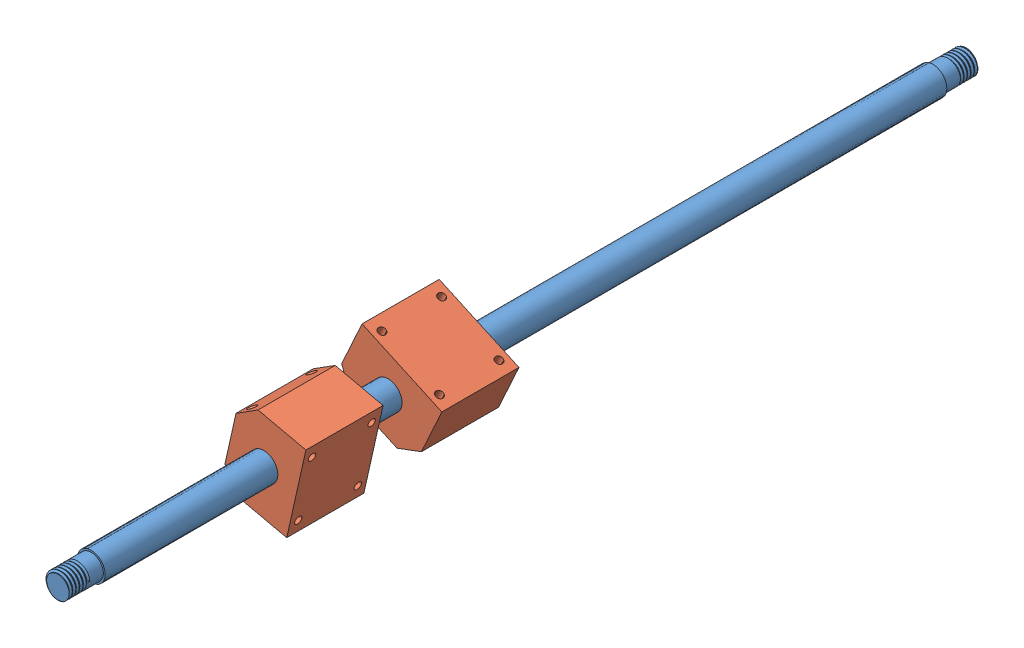
SolidWorks assembly X slide, configuration Default. Lengths in mm.
Overall size (61.48 57.21 520.39).
3 component instances, 2 part files, 2 mates.
Components (placement in the parent):
- X rod-1: X rod [Default] at (118.7688 177.4566 348.0591) size (16 16 520.39)
- sliding block-1: sliding block [Default] at (110.6674 159.7192 206.2391) x (-0.909614 0.415455 0) z (0.415455 0.909614 0) size (50 44 38.5)
- sliding block-2: sliding block [Default] at (99.7413 181.7233 277.1167) x (-0.218802 -0.975769 0) z (0.975769 -0.218802 0) size (50 44 38.5)
Mates (geometry in assembly coordinates):
- Concentric1: concentric aligned: cylinder of X rod-1 through (118.7688 177.4566 417.0821) axis (0 0 1) radius 8; cylinder of sliding block-1 through (118.7688 177.4566 184.2391) axis (0 0 1) radius 8
- Concentric2: concentric anti-aligned: cylinder of X rod-1 through (118.7688 177.4566 417.0821) axis (0 0 1) radius 8; cylinder of sliding block-2 through (118.7688 177.4566 299.1167) axis (0 0 -1) radius 8
